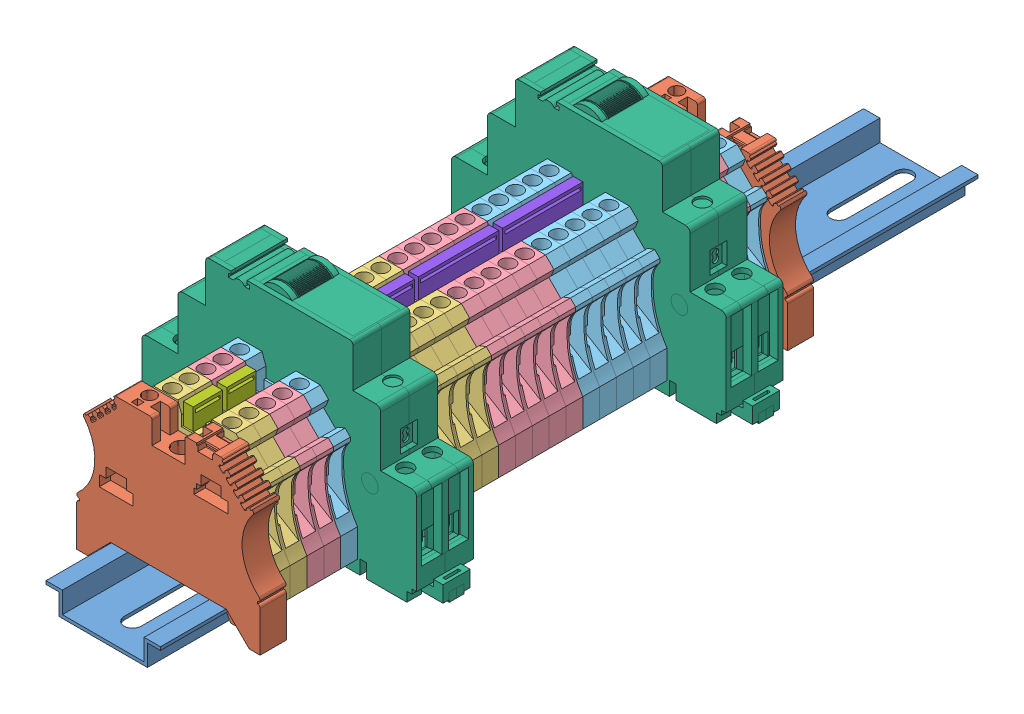
SolidWorks assembly Power Schreibtisch, configuration Standard. Lengths in mm.
Overall size (88.06 71.09 250).
33 component instances, 8 part files, 105 mates.
Components (placement in the parent):
- Hutschiene-1: Hutschiene [250] at (-17.5 -7.5 0) x (-1 0 0) z (0 0 -1) size (35 7.5 250)
- WEW_35_2-1: WEW_35_2 [Standard] at (10.49 -7 -20) x (0 0 -1) z (0 1 0) size (8 56.1 46.5)
- UT_2.5-1: UT_2.5 [Standard] at (-48.6989 10.6178 -28) x (0.992546 -0.121869 0) z (0 0 1) size (49.27 50.96 5.15)
- UT_2.5-2: UT_2.5 [Standard] at (-48.6989 10.6178 -33.15) x (0.992546 -0.121869 0) z (0 0 1) size (49.27 50.96 5.15)
- UT_2.5_BU-1: UT_2.5_BU [Standard] at (-48.6989 10.6178 -38.3) x (0.992546 -0.121869 0) z (0 0 1) size (49.27 50.96 5.15)
- UT_2.5_BU-2: UT_2.5_BU [Standard] at (-48.6989 10.6178 -43.45) x (0.992546 -0.121869 0) z (0 0 1) size (49.27 50.96 5.15)
- UT_2.5_PE-1: UT_2.5_PE [Standard] at (-48.6989 10.6178 -48.6) x (0.992546 -0.121869 0) z (0 0 1) size (49.27 50.96 5.15)
- Finder 20.22.8.230.400-1: Finder 20.22.8.230.400 [Standard] at (-33.2328 48.1119 -81.3028) x (1 0 0) z (0 -1 0) size (88.06 17.68 62.84)
- UT_2.5-3: UT_2.5 [Standard] at (-48.6989 10.6178 -71.15) x (0.992546 -0.121869 0) z (0 0 1) size (49.27 50.96 5.15)
- UT_2.5-4: UT_2.5 [Standard] at (-48.6989 10.6178 -76.3) x (0.992546 -0.121869 0) z (0 0 1) size (49.27 50.96 5.15)
- UT_2.5-5: UT_2.5 [Standard] at (-48.6989 10.6178 -81.45) x (0.992546 -0.121869 0) z (0 0 1) size (49.27 50.96 5.15)
- UT_2.5-6: UT_2.5 [Standard] at (-48.6989 10.6178 -86.6) x (0.992546 -0.121869 0) z (0 0 1) size (49.27 50.96 5.15)
- UT_2.5-7: UT_2.5 [Standard] at (-48.6989 10.6178 -91.75) x (0.992546 -0.121869 0) z (0 0 1) size (49.27 50.96 5.15)
- UT_2.5_BU-3: UT_2.5_BU [Standard] at (-48.6989 10.6178 -96.9) x (0.992546 -0.121869 0) z (0 0 1) size (49.27 50.96 5.15)
- UT_2.5_BU-4: UT_2.5_BU [Standard] at (-48.6989 10.6178 -102.05) x (0.992546 -0.121869 0) z (0 0 1) size (49.27 50.96 5.15)
- UT_2.5_BU-5: UT_2.5_BU [Standard] at (-48.6989 10.6178 -107.2) x (0.992546 -0.121869 0) z (0 0 1) size (49.27 50.96 5.15)
- UT_2.5_BU-6: UT_2.5_BU [Standard] at (-48.6989 10.6178 -112.35) x (0.992546 -0.121869 0) z (0 0 1) size (49.27 50.96 5.15)
- UT_2.5_BU-7: UT_2.5_BU [Standard] at (-48.6989 10.6178 -117.5) x (0.992546 -0.121869 0) z (0 0 1) size (49.27 50.96 5.15)
- UT_2.5_PE-2: UT_2.5_PE [Standard] at (-48.6989 10.6178 -122.65) x (0.992546 -0.121869 0) z (0 0 1) size (49.27 50.96 5.15)
- UT_2.5_PE-3: UT_2.5_PE [Standard] at (-48.6989 10.6178 -127.8) x (0.992546 -0.121869 0) z (0 0 1) size (49.27 50.96 5.15)
- UT_2.5_PE-4: UT_2.5_PE [Standard] at (-48.6989 10.6178 -132.95) x (0.992546 -0.121869 0) z (0 0 1) size (49.27 50.96 5.15)
- UT_2.5_PE-5: UT_2.5_PE [Standard] at (-48.6989 10.6178 -138.1) x (0.992546 -0.121869 0) z (0 0 1) size (49.27 50.96 5.15)
- UT_2.5_PE-6: UT_2.5_PE [Standard] at (-48.6989 10.6178 -143.25) x (0.992546 -0.121869 0) z (0 0 1) size (49.27 50.96 5.15)
- Finder 20.22.8.230.400-2: Finder 20.22.8.230.400 [Standard] at (-33.2328 48.1119 -175.9528) x (1 0 0) z (0 -1 0) size (88.06 17.68 62.84)
- UT_2.5-8: UT_2.5 [Standard] at (-48.6989 10.6178 -165.8) x (0.992546 -0.121869 0) z (0 0 1) size (49.27 50.96 5.15)
- UT_2.5_BU-8: UT_2.5_BU [Standard] at (-48.6989 10.6178 -170.95) x (0.992546 -0.121869 0) z (0 0 1) size (49.27 50.96 5.15)
- UT_2.5_PE-7: UT_2.5_PE [Standard] at (-48.6989 10.6178 -176.1) x (0.992546 -0.121869 0) z (0 0 1) size (49.27 50.96 5.15)
- WEW_35_2-2: WEW_35_2 [Standard] at (10.49 -7 -181.25) x (0 0 -1) z (0 1 0) size (8 56.1 46.5)
- FBS_2-5-1: FBS_2-5 [Standard] at (-24.1072 49.175 -86.835) size (3 22.98 9)
- FBS_2-5-3: FBS_2-5 [Standard] at (-24.1072 49.175 -97.135) size (3 22.98 9)
- FBS_5_5-1: FBS_5_5 [Standard] at (-24.1072 48.875 -130.01) size (3 22.98 24.6)
- FBS_5_5-2: FBS_5_5 [Standard] at (-24.1072 48.875 -155.735) size (3 22.98 24.6)
- FBS_5_5-3: FBS_5_5 [Standard] at (-24.1072 48.875 -181.485) size (3 22.98 24.6)
Mates (geometry in assembly coordinates):
- Deckungsgleich1: coincident: plane of Hutschiene-1 through (-17.5 -7.5 0) normal (0 0 1); plane of assembly through (0 0 0) normal (0 0 1)
- Deckungsgleich2: coincident: plane of Hutschiene-1 through (-35 0 -250) normal (0 1 0); plane of assembly through (0 0 0) normal (0 1 0)
- Deckungsgleich3: coincident: plane of Hutschiene-1 through (0 0 -250) normal (1 0 0); plane of assembly through (0 0 0) normal (1 0 0)
- Deckungsgleich4: coincident: plane of Hutschiene-1 through (-35 0 -250) normal (0 1 0); plane of WEW_35_2-1 through (-35.26 0 -28) normal (0 -1 0)
- Tangential1: tangent: plane of Hutschiene-1 through (0 0 -250) normal (1 0 0); cylinder of WEW_35_2-1 through (2 -1.4 -24) axis (0 0 -1) radius 2
- Abstand1: distance = 20 mm: plane of Hutschiene-1 through (-17.5 -7.5 0) normal (0 0 1); plane of WEW_35_2-1 through (-17.56 0 -20) normal (0 0 1)
- Deckungsgleich6: coincident: plane of WEW_35_2-1 through (-17.56 0 -28) normal (0 0 -1); plane of UT_2.5-1 through (0 0 -28) normal (0 0 1)
- Deckungsgleich7: coincident: plane of UT_2.5-1 through (0 0 -33.15) normal (0 0 -1); plane of UT_2.5-2 through (0 0 -33.15) normal (0 0 1)
- Deckungsgleich10: coincident: plane of Hutschiene-1 through (-35 0 -250) normal (0 1 0); plane of UT_2.5-1 through (-7.7 0 -28) normal (0 -1 0)
- Deckungsgleich11: coincident: plane of Hutschiene-1 through (-35 0 -250) normal (0 1 0); plane of UT_2.5-2 through (-7.7 0 -33.15) normal (0 -1 0)
- Deckungsgleich12: coincident: plane of Hutschiene-1 through (-35 0 -250) normal (0 1 0); plane of UT_2.5_BU-1 through (-7.7 0 -38.3) normal (0 -1 0)
- Deckungsgleich13: coincident: plane of Hutschiene-1 through (-35 0 -250) normal (0 1 0); plane of UT_2.5_PE-1 through (-7.7 0 -48.6) normal (0 -1 0)
- Deckungsgleich14: coincident: plane of Hutschiene-1 through (0 0 -250) normal (1 0 0); plane of UT_2.5-1 through (0 -1.1 -28) normal (-1 0 0)
- Deckungsgleich15: coincident: plane of Hutschiene-1 through (0 0 -250) normal (1 0 0); plane of UT_2.5-2 through (0 -1.1 -33.15) normal (-1 0 0)
- Deckungsgleich16: coincident: plane of Hutschiene-1 through (0 0 -250) normal (1 0 0); plane of UT_2.5_BU-1 through (0 -1.1 -38.3) normal (-1 0 0)
- Deckungsgleich17: coincident: plane of Hutschiene-1 through (0 0 -250) normal (1 0 0); plane of UT_2.5_PE-1 through (0 -1.1 -48.6) normal (-1 0 0)
- Deckungsgleich19: coincident: plane of Hutschiene-1 through (-35 0 -250) normal (0 1 0); plane of UT_2.5-3 through (-7.7 0 -71.15) normal (0 -1 0)
- Deckungsgleich20: coincident: plane of Hutschiene-1 through (0 0 -250) normal (1 0 0); plane of UT_2.5-3 through (0 -1.1 -71.15) normal (-1 0 0)
- Deckungsgleich22: coincident: plane of UT_2.5-1 through (-18.35 21.85 -28.475) normal (0 0 -1); plane of FBS_2-5-1 through (-18.5 39.7 -28.475) normal (0 0 1)
- Deckungsgleich23: coincident: plane of UT_2.5_BU-1 through (-16.65 21.85 -42.8) normal (0 0 1); plane of ? through (-14.8214 35.054 -42.8) normal (0 0 -1)
- Deckungsgleich24: coincident: plane of UT_2.5-1 through (-21.5 36.703 -28) normal (1 0 0); plane of FBS_2-5-1 through (-21.5 41.9423 -62.735) normal (-1 0 0)
- Deckungsgleich25: coincident: plane of UT_2.5-2 through (-13.5 33.5 -33.15) normal (-1 0 0); plane of ? through (-13.5 38.7586 -42.5345) normal (1 0 0)
- Deckungsgleich26: coincident: plane of UT_2.5-2 through (-12.3 40 -33.15) normal (0 1 0); plane of ? through (-13.5 40 -13.3) normal (0 1 0)
- Deckungsgleich27: coincident: plane of UT_2.5-1 through (-30.1 40 -28) normal (0 1 0); plane of FBS_2-5-1 through (-18.5 40 -7.975) normal (0 1 0)
- Deckungsgleich28: coincident: plane of Hutschiene-1 through (-5 0 -250) normal (0 1 0); plane of Finder 20.22.8.230.400-1 through (-35.4105 0 -53.74) normal (0 -1 0)
- Deckungsgleich29: coincident: plane of Hutschiene-1 through (-5 0 -250) normal (0 1 0); plane of Finder 20.22.8.230.400-2 through (-35.4105 0 -148.39) normal (0 -1 0)
- Deckungsgleich30: coincident: plane of UT_2.5_PE-1 through (0 0 -53.75) normal (0 0 -1); plane of Finder 20.22.8.230.400-1 through (33.0017 62.5812 -53.75) normal (0 0 1)
- Deckungsgleich32: coincident: plane of Hutschiene-1 through (0 0 -250) normal (1 0 0); plane of Finder 20.22.8.230.400-1 through (0 -0.76 -67.785) normal (-1 0 0)
- Deckungsgleich33: coincident: plane of Hutschiene-1 through (0 0 -250) normal (1 0 0); plane of Finder 20.22.8.230.400-2 through (0 -0.76 -162.435) normal (-1 0 0)
- Deckungsgleich34: coincident: plane of UT_2.5_BU-1 through (0 0 -43.45) normal (0 0 -1); plane of UT_2.5_BU-2 through (0 0 -43.45) normal (0 0 1)
- Deckungsgleich37: coincident: plane of Hutschiene-1 through (-35 0 -250) normal (0 1 0); plane of UT_2.5_BU-2 through (-7.7 0 -43.45) normal (0 -1 0)
- Deckungsgleich38: coincident: plane of Hutschiene-1 through (-35 0 -250) normal (0 1 0); plane of UT_2.5_BU-3 through (-7.7 0 -96.9) normal (0 -1 0)
- Deckungsgleich39: coincident: plane of Hutschiene-1 through (0 0 -250) normal (1 0 0); plane of UT_2.5_BU-2 through (0 -1.1 -43.45) normal (-1 0 0)
- Deckungsgleich40: coincident: plane of Hutschiene-1 through (0 0 -250) normal (1 0 0); plane of UT_2.5_BU-3 through (0 -1.1 -96.9) normal (-1 0 0)
- Deckungsgleich41: coincident: plane of UT_2.5_BU-1 through (-21.5 36.703 -38.3) normal (1 0 0); plane of FBS_2-5-3 through (-21.5 41.9423 -73.035) normal (-1 0 0)
- Deckungsgleich42: coincident anti-aligned: plane of UT_2.5_BU-3 through (-13.5 33.5 -53.75) normal (-1 0 0); plane of ? through (-13.5 38.7586 -57.9845) normal (1 0 0)
- Deckungsgleich43: coincident: plane of UT_2.5_BU-1 through (-18.35 21.85 -38.775) normal (0 0 -1); plane of FBS_2-5-3 through (-18.5 39.7 -38.775) normal (0 0 1)
- Deckungsgleich44: coincident anti-aligned: plane of UT_2.5_BU-3 through (-16.65 21.85 -58.25) normal (0 0 1); plane of ? through (-14.8214 35.054 -58.25) normal (0 0 -1)
- Deckungsgleich45: coincident: plane of UT_2.5_BU-1 through (-30.1 40 -38.3) normal (0 1 0); plane of FBS_2-5-3 through (-18.5 40 -18.275) normal (0 1 0)
- Deckungsgleich46: coincident aligned: plane of UT_2.5_BU-3 through (-12.3 40 -53.75) normal (0 1 0); plane of ? through (-13.5 40 -28.75) normal (0 1 0)
- Deckungsgleich47: coincident: plane of UT_2.5-2 through (0 0 -38.3) normal (0 0 -1); plane of UT_2.5_BU-1 through (0 0 -38.3) normal (0 0 1)
- Deckungsgleich48: coincident: plane of UT_2.5_BU-2 through (0 0 -48.6) normal (0 0 -1); plane of UT_2.5_PE-1 through (0 0 -48.6) normal (0 0 1)
- Deckungsgleich49: coincident: plane of UT_2.5-3 through (0 0 -71.15) normal (0 0 1); plane of Finder 20.22.8.230.400-1 through (33.0013 -10.3807 -71.15) normal (0 0 -1)
- Deckungsgleich50: coincident: plane of UT_2.5-3 through (0 0 -76.3) normal (0 0 -1); plane of UT_2.5-4 through (0 0 -76.3) normal (0 0 1)
- Deckungsgleich51: coincident: plane of UT_2.5-4 through (0 0 -81.45) normal (0 0 -1); plane of UT_2.5-5 through (0 0 -81.45) normal (0 0 1)
- Deckungsgleich52: coincident: plane of UT_2.5-5 through (0 0 -86.6) normal (0 0 -1); plane of UT_2.5-6 through (0 0 -86.6) normal (0 0 1)
- Deckungsgleich53: coincident: plane of UT_2.5-6 through (0 0 -91.75) normal (0 0 -1); plane of UT_2.5-7 through (0 0 -91.75) normal (0 0 1)
- Deckungsgleich54: coincident: plane of Hutschiene-1 through (-35 0 -250) normal (0 1 0); plane of UT_2.5-4 through (-7.7 0 -76.3) normal (0 -1 0)
- Deckungsgleich55: coincident: plane of Hutschiene-1 through (-35 0 -250) normal (0 1 0); plane of UT_2.5-5 through (-7.7 0 -81.45) normal (0 -1 0)
- Deckungsgleich56: coincident: plane of Hutschiene-1 through (-35 0 -250) normal (0 1 0); plane of UT_2.5-6 through (-7.7 0 -86.6) normal (0 -1 0)
- Deckungsgleich57: coincident: plane of Hutschiene-1 through (-35 0 -250) normal (0 1 0); plane of UT_2.5-7 through (-7.7 0 -91.75) normal (0 -1 0)
- Deckungsgleich58: coincident: plane of Hutschiene-1 through (0 0 -250) normal (1 0 0); plane of UT_2.5-4 through (0 -1.1 -76.3) normal (-1 0 0)
- Deckungsgleich59: coincident: plane of Hutschiene-1 through (0 0 -250) normal (1 0 0); plane of UT_2.5-5 through (0 -1.1 -81.45) normal (-1 0 0)
- Deckungsgleich60: coincident: plane of Hutschiene-1 through (0 0 -250) normal (1 0 0); plane of UT_2.5-6 through (0 -1.1 -86.6) normal (-1 0 0)
- Deckungsgleich61: coincident: plane of Hutschiene-1 through (0 0 -250) normal (1 0 0); plane of UT_2.5-7 through (0 -1.1 -91.75) normal (-1 0 0)
- Deckungsgleich62: coincident: plane of UT_2.5_BU-3 through (0 0 -102.05) normal (0 0 -1); plane of UT_2.5_BU-4 through (0 0 -102.05) normal (0 0 1)
- Deckungsgleich63: coincident: plane of UT_2.5_BU-4 through (0 0 -107.2) normal (0 0 -1); plane of UT_2.5_BU-5 through (0 0 -107.2) normal (0 0 1)
- Deckungsgleich64: coincident: plane of UT_2.5_BU-5 through (0 0 -112.35) normal (0 0 -1); plane of UT_2.5_BU-6 through (0 0 -112.35) normal (0 0 1)
- Deckungsgleich65: coincident: plane of UT_2.5_BU-6 through (0 0 -117.5) normal (0 0 -1); plane of UT_2.5_BU-7 through (0 0 -117.5) normal (0 0 1)
- Deckungsgleich66: coincident: plane of UT_2.5_BU-7 through (0 0 -122.65) normal (0 0 -1); plane of UT_2.5_PE-2 through (0 0 -122.65) normal (0 0 1)
- Deckungsgleich67: coincident: plane of UT_2.5_PE-2 through (0 0 -127.8) normal (0 0 -1); plane of UT_2.5_PE-3 through (0 0 -127.8) normal (0 0 1)
- Deckungsgleich68: coincident: plane of UT_2.5_PE-3 through (0 0 -132.95) normal (0 0 -1); plane of UT_2.5_PE-4 through (0 0 -132.95) normal (0 0 1)
- Deckungsgleich69: coincident: plane of UT_2.5_PE-4 through (0 0 -138.1) normal (0 0 -1); plane of UT_2.5_PE-5 through (0 0 -138.1) normal (0 0 1)
- Deckungsgleich70: coincident: plane of UT_2.5_PE-5 through (0 0 -143.25) normal (0 0 -1); plane of UT_2.5_PE-6 through (0 0 -143.25) normal (0 0 1)
- Deckungsgleich71: coincident: plane of UT_2.5_PE-6 through (0 0 -148.4) normal (0 0 -1); plane of Finder 20.22.8.230.400-2 through (33.0017 62.5812 -148.4) normal (0 0 1)
- Deckungsgleich72: coincident: plane of Finder 20.22.8.230.400-2 through (33.0013 -10.3807 -165.8) normal (0 0 -1); plane of UT_2.5-8 through (0 0 -165.8) normal (0 0 1)
- Deckungsgleich73: coincident: plane of UT_2.5-8 through (0 0 -170.95) normal (0 0 -1); plane of UT_2.5_BU-8 through (0 0 -170.95) normal (0 0 1)
- Deckungsgleich74: coincident: plane of UT_2.5_BU-8 through (0 0 -176.1) normal (0 0 -1); plane of UT_2.5_PE-7 through (0 0 -176.1) normal (0 0 1)
- Deckungsgleich75: coincident: plane of UT_2.5_PE-7 through (0 0 -181.25) normal (0 0 -1); plane of WEW_35_2-2 through (-17.56 0 -181.25) normal (0 0 1)
- Deckungsgleich76: coincident: plane of UT_2.5-7 through (0 0 -96.9) normal (0 0 -1); plane of UT_2.5_BU-3 through (0 0 -96.9) normal (0 0 1)
- Deckungsgleich77: coincident: plane of Hutschiene-1 through (-35 0 -250) normal (0 1 0); plane of UT_2.5_BU-4 through (-7.7 0 -102.05) normal (0 -1 0)
- Deckungsgleich78: coincident: plane of Hutschiene-1 through (-35 0 -250) normal (0 1 0); plane of UT_2.5_BU-5 through (-7.7 0 -107.2) normal (0 -1 0)
- Deckungsgleich79: coincident: plane of Hutschiene-1 through (-35 0 -250) normal (0 1 0); plane of UT_2.5_BU-6 through (-7.7 0 -112.35) normal (0 -1 0)
- Deckungsgleich80: coincident: plane of Hutschiene-1 through (-35 0 -250) normal (0 1 0); plane of UT_2.5_BU-7 through (-7.7 0 -117.5) normal (0 -1 0)
- Deckungsgleich81: coincident: plane of Hutschiene-1 through (-35 0 -250) normal (0 1 0); plane of UT_2.5_PE-2 through (-7.7 0 -122.65) normal (0 -1 0)
- Deckungsgleich82: coincident: plane of Hutschiene-1 through (-35 0 -250) normal (0 1 0); plane of UT_2.5_PE-3 through (-7.7 0 -127.8) normal (0 -1 0)
- Deckungsgleich83: coincident: plane of Hutschiene-1 through (-35 0 -250) normal (0 1 0); plane of UT_2.5_PE-5 through (-7.7 0 -138.1) normal (0 -1 0)
- Deckungsgleich84: coincident: plane of Hutschiene-1 through (-35 0 -250) normal (0 1 0); plane of UT_2.5_PE-4 through (-7.7 0 -132.95) normal (0 -1 0)
- Deckungsgleich85: coincident: plane of Hutschiene-1 through (-35 0 -250) normal (0 1 0); plane of UT_2.5_PE-6 through (-7.7 0 -143.25) normal (0 -1 0)
- Deckungsgleich86: coincident: plane of Hutschiene-1 through (-35 0 -250) normal (0 1 0); plane of UT_2.5-8 through (-7.7 0 -165.8) normal (0 -1 0)
- Deckungsgleich87: coincident: plane of Hutschiene-1 through (-35 0 -250) normal (0 1 0); plane of UT_2.5_BU-8 through (-7.7 0 -170.95) normal (0 -1 0)
- Deckungsgleich88: coincident: plane of Hutschiene-1 through (-35 0 -250) normal (0 1 0); plane of UT_2.5_PE-7 through (-7.7 0 -176.1) normal (0 -1 0)
- Deckungsgleich89: coincident: plane of Hutschiene-1 through (-35 0 -250) normal (0 1 0); plane of WEW_35_2-2 through (-35.26 0 -189.25) normal (0 -1 0)
- Deckungsgleich90: coincident: plane of Hutschiene-1 through (0 0 -250) normal (1 0 0); plane of UT_2.5_BU-4 through (0 -1.1 -102.05) normal (-1 0 0)
- Deckungsgleich91: coincident: plane of Hutschiene-1 through (0 0 -250) normal (1 0 0); plane of UT_2.5_BU-5 through (0 -1.1 -107.2) normal (-1 0 0)
- Deckungsgleich92: coincident: plane of Hutschiene-1 through (0 0 -250) normal (1 0 0); plane of UT_2.5_BU-6 through (0 -1.1 -112.35) normal (-1 0 0)
- Deckungsgleich93: coincident: plane of Hutschiene-1 through (0 0 -250) normal (1 0 0); plane of UT_2.5_BU-7 through (0 -1.1 -117.5) normal (-1 0 0)
- Deckungsgleich94: coincident: plane of Hutschiene-1 through (0 0 -250) normal (1 0 0); plane of UT_2.5_PE-2 through (0 -1.1 -122.65) normal (-1 0 0)
- Deckungsgleich95: coincident: plane of Hutschiene-1 through (0 0 -250) normal (1 0 0); plane of UT_2.5_PE-3 through (0 -1.1 -127.8) normal (-1 0 0)
- Deckungsgleich96: coincident: plane of Hutschiene-1 through (0 0 -250) normal (1 0 0); plane of UT_2.5_PE-4 through (0 -1.1 -132.95) normal (-1 0 0)
- Deckungsgleich97: coincident: plane of Hutschiene-1 through (0 0 -250) normal (1 0 0); plane of UT_2.5_PE-5 through (0 -1.1 -138.1) normal (-1 0 0)
- Deckungsgleich98: coincident: plane of Hutschiene-1 through (0 0 -250) normal (1 0 0); plane of UT_2.5_PE-6 through (0 -1.1 -143.25) normal (-1 0 0)
- Deckungsgleich99: coincident: plane of Hutschiene-1 through (0 0 -250) normal (1 0 0); plane of UT_2.5-8 through (0 -1.1 -165.8) normal (-1 0 0)
- Deckungsgleich100: coincident: plane of Hutschiene-1 through (0 0 -250) normal (1 0 0); plane of UT_2.5_BU-8 through (0 -1.1 -170.95) normal (-1 0 0)
- Deckungsgleich101: coincident: plane of Hutschiene-1 through (0 0 -250) normal (1 0 0); plane of UT_2.5_PE-7 through (0 -1.1 -176.1) normal (-1 0 0)
- Tangential2: tangent: plane of Hutschiene-1 through (0 0 -250) normal (1 0 0); cylinder of WEW_35_2-2 through (2 -1.4 -185.25) axis (0 0 -1) radius 2
- Deckungsgleich102: coincident: plane of UT_2.5-3 through (-21.5 36.703 -71.15) normal (1 0 0); plane of FBS_5_5-1 through (-21.5 38.7586 -85.5845) normal (-1 0 0)
- Deckungsgleich103: coincident: plane of UT_2.5_BU-4 through (-21.5 36.703 -102.05) normal (1 0 0); plane of FBS_5_5-2 through (-21.5 38.7586 -111.3095) normal (-1 0 0)
- Deckungsgleich104: coincident: plane of UT_2.5_PE-3 through (-21.5 36.703 -127.8) normal (1 0 0); plane of FBS_5_5-3 through (-21.5 38.7586 -137.0595) normal (-1 0 0)
- Deckungsgleich105: coincident: plane of UT_2.5-7 through (-21.5 21.85 -96.25) normal (0 0 1); plane of FBS_5_5-1 through (-18.5 39.7 -96.25) normal (0 0 -1)
- Deckungsgleich106: coincident: plane of UT_2.5_BU-3 through (-18.35 21.85 -97.375) normal (0 0 -1); plane of FBS_5_5-2 through (-18.5 39.7 -97.375) normal (0 0 1)
- Deckungsgleich107: coincident: plane of UT_2.5_PE-2 through (-18.35 21.85 -123.125) normal (0 0 -1); plane of FBS_5_5-3 through (-18.5 39.7 -123.125) normal (0 0 1)
- Deckungsgleich108: coincident: plane of UT_2.5-7 through (-30.1 40 -91.75) normal (0 1 0); plane of FBS_5_5-1 through (-18.5 40 -82.05) normal (0 1 0)
- Deckungsgleich109: coincident: plane of UT_2.5_BU-3 through (-30.1 40 -96.9) normal (0 1 0); plane of FBS_5_5-2 through (-18.5 40 -107.775) normal (0 1 0)
- Deckungsgleich110: coincident: plane of UT_2.5_PE-2 through (-30.1 40 -122.65) normal (0 1 0); plane of FBS_5_5-3 through (-18.5 40 -133.525) normal (0 1 0)
